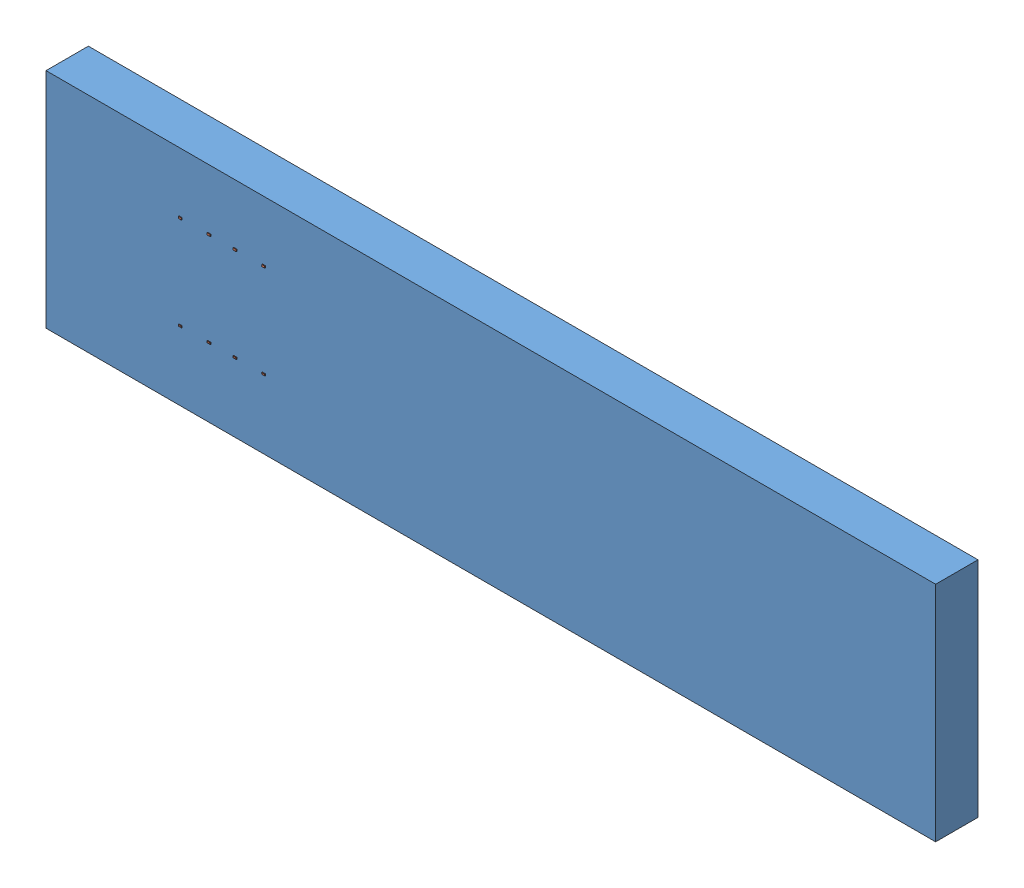
SolidWorks assembly Assem2, configuration Default. Lengths in mm.
Overall size (80.01 20.07 7.06).
2 component instances, 2 part files, 1 mates.
Components (placement in the parent):
- 2cmx8cm perfboard-1: 2cmx8cm perfboard [Default] at origin size (80.01 20.07 3.81)
- NE555-2: NE555 [Default] at (-228.6516 -10.7328 15.927) x (-1 0 0) z (0 -1 0) size (10.27 7.06 8.8)
Mates (geometry in assembly coordinates):
- Tangent1: tangent anti-aligned: plane of 2cmx8cm perfboard-1 through (0 0 0) normal (0 0 -1); face of NE555-2
